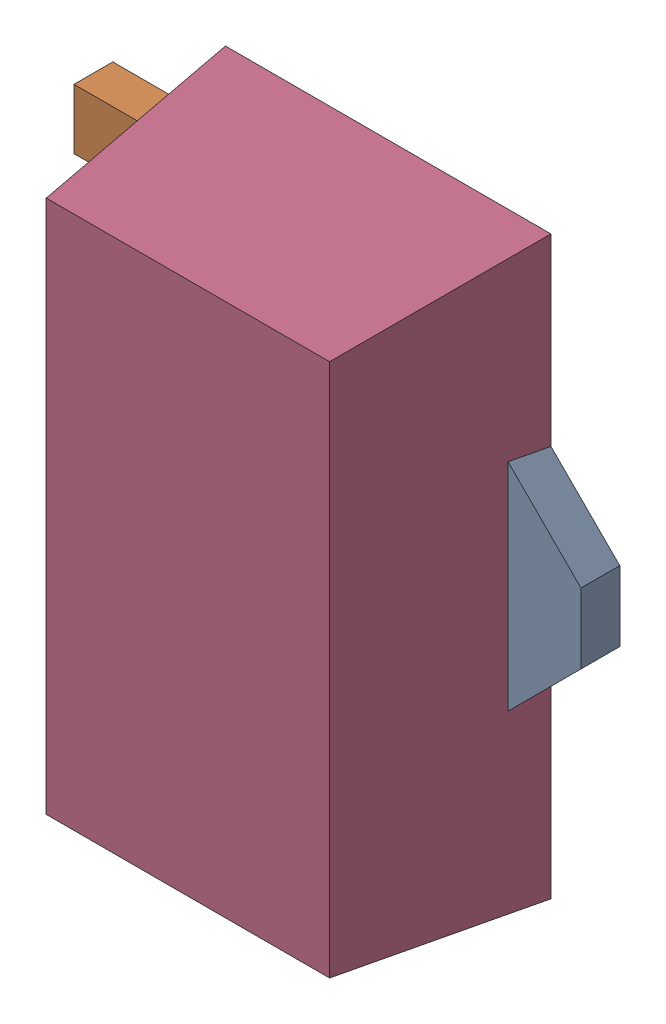
SolidWorks assembly 6517555664, configuration 默认. Lengths in mm.
Overall size (4.05 4.6 1.6).
6 component instances, 4 part files, 0 mates.
Components (placement in the parent):
- CenterLeader-1: CenterLeader [默认] at (-1.3 -2.3 0) size (4.05 1.83 0.31)
  - Open_CASCADE_STEP_translator_6.8_1.1.1-1: Open_CASCADE_STEP_translator_6.8_1.1.1 [默认] at origin size (4.05 1.83 0.31)
- top-1: top [默认] at (-1.3 -2.3 0) size (1.2 0.48 0.31)
- bottom-1: bottom [默认] at (-1.3 -2.3 0) size (1.2 0.48 0.31)
- Body-1: Body [默认] at (-1.3 -2.3 0) size (2.6 4.6 1.6)
  - Open_CASCADE_STEP_translator_6.8_1.4.1-1: Open_CASCADE_STEP_translator_6.8_1.4.1 [默认] at origin size (2.6 4.6 1.6)
